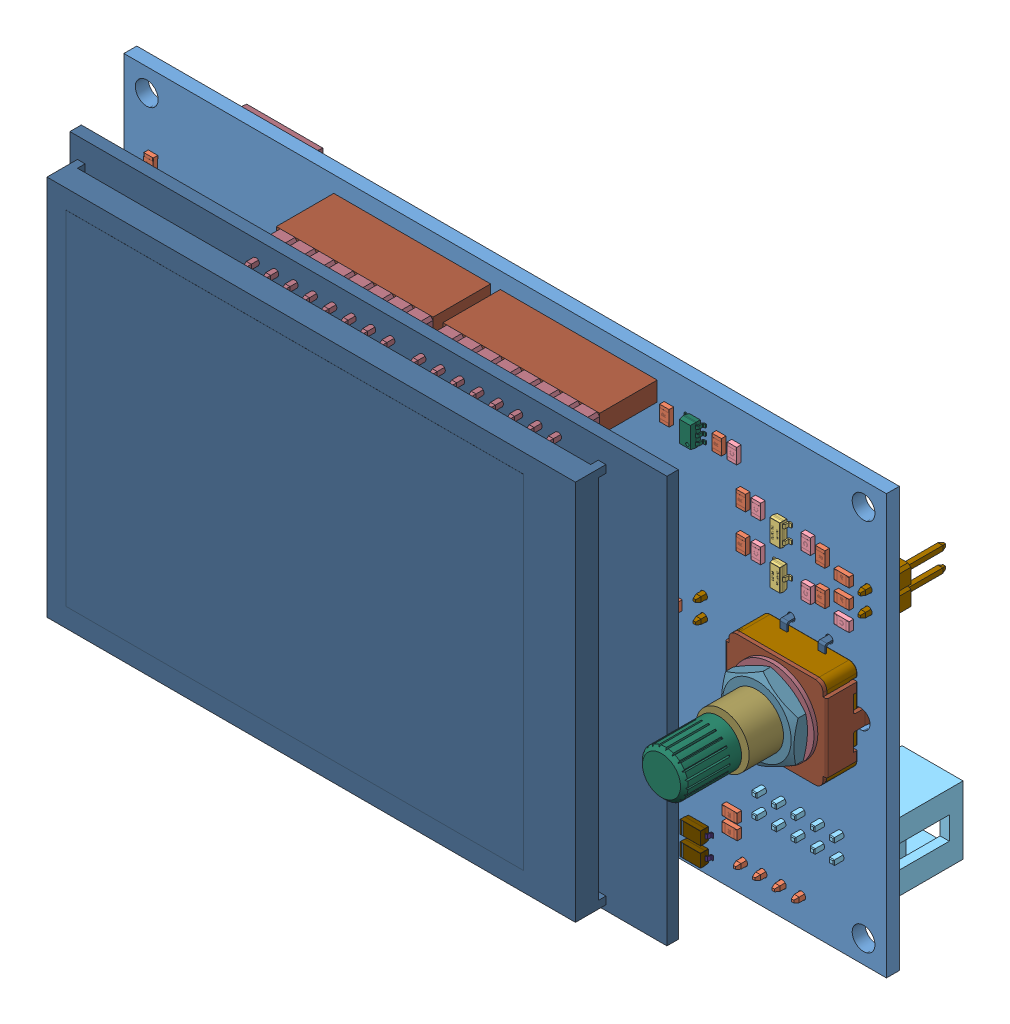
SolidWorks assembly JBC_SolderingIron, configuration Default. Lengths in mm.
Overall size (100 55 34.69).
305 component instances, 58 part files, 0 mates.
Components (placement in the parent):
- Board-1: Board [Default] at origin size (100 55 1.69)
  - Open CASCADE STEP translator 6.8 1.1.1-1: Open CASCADE STEP translator 6.8 1.1.1 [Default] at (0 0 -1.6914) size (100 55 1.69)
- R35-1: R35 [Default] at origin size (1.25 2 0.61)
  - 0805_Fekete_R-1: 0805_Fekete_R [Default] at (119.0962 50.0352 -0.35) x (0 -1 0) z (0 0 -1) size (2 1.25 0.61)
- R34-1: R34 [Default] at origin size (2 1.25 0.61)
  - 0805_Fekete_R-1: 0805_Fekete_R [Default] at (99.4752 5.4168 -0.35) x (-1 0 0) z (0 0 -1) size (2 1.25 0.61)
- R33-1: R33 [Default] at origin size (1.25 2 0.61)
  - 0805_Fekete_R-1: 0805_Fekete_R [Default] at (54.2688 39.2928 -0.35) x (0 1 0) z (0 0 -1) size (2 1.25 0.61)
- Q4-1: Q4 [Default] at origin size (2.5 3.01 1.1)
  - SOT23-1: SOT23 [Default] at (86.4599 44.3231 0) x (0 -1 0) z (-1 0 0) size (3.01 1.1 2.5)
- C31-1: C31 [Default] at origin size (1.25 2 0.61)
  - 0805_Barna_C-1: 0805_Barna_C [Default] at (121.0963 50.0351 -0.35) x (0 -1 0) z (0 0 -1) size (2 1.25 0.61)
- C14-1: C14 [Default] at origin size (1.25 2 0.61)
  - 0805_Barna_C-1: 0805_Barna_C [Default] at (52.3637 39.8009 -0.35) x (0 1 0) z (0 0 -1) size (2 1.25 0.61)
- C29-1: C29 [Default] at origin size (11.6 10.3 10.2)
  - User_Library-ALU-G-1: User_Library-ALU-G [Default] at (26.6701 17.1449 -1.6914) x (1 0 0) z (0 0 -1) size (11.6 10.3 10.2)
    - Pins_1-1: Pins_1 [Default] at origin size (11.6 0.9 0.35)
    - Fuss_1-1: Fuss_1 [Default] at origin size (10.3 10.3 1)
    - K_X_F6rper_1-1: K_X_F6rper_1 [Default] at origin size (10 10 9.5)
    - Beschriftung_1-1: Beschriftung_1 [Default] at origin size (7.49 8.07 0.06)
- C30-1: C30 [Default] at origin size (11.6 10.3 10.2)
  - User_Library-ALU-G-1: User_Library-ALU-G [Default] at (26.6701 28.5749 -1.6914) x (1 0 0) z (0 0 -1) size (11.6 10.3 10.2)
    - Pins_1-1: Pins_1 [Default] at origin size (11.6 0.9 0.35)
    - Fuss_1-1: Fuss_1 [Default] at origin size (10.3 10.3 1)
    - K_X_F6rper_1-1: K_X_F6rper_1 [Default] at origin size (10 10 9.5)
    - Beschriftung_1-1: Beschriftung_1 [Default] at origin size (7.49 8.07 0.06)
- J4-1: J4 [Default] at origin size (2.5 5.08 11.2)
  - SIL2-1: SIL2 [Default] at (97.6199 41.7829 -1.7914) x (0 -1 0) z (-1 0 0) size (5.08 11.2 2.5)
- R28-1: R28 [Default] at origin size (2 1.25 0.61)
  - 0805_Fekete_R-1: 0805_Fekete_R [Default] at (75.2338 46.5262 -0.35) x (1 0 0) z (0 0 -1) size (2 1.25 0.61)
- R27-1: R27 [Default] at origin size (2 1.25 0.61)
  - 0805_Fekete_R-1: 0805_Fekete_R [Default] at (75.2338 44.6212 -0.35) x (1 0 0) z (0 0 -1) size (2 1.25 0.61)
- C12-1: C12 [Default] at origin size (1.25 2 0.61)
  - 0805_Barna_C-1: 0805_Barna_C [Default] at (57.2213 33.6341 -0.35) x (0 -1 0) z (0 0 -1) size (2 1.25 0.61)
- C10-1: C10 [Default] at origin size (1.25 2 0.61)
  - 0805_Barna_C-1: 0805_Barna_C [Default] at (64.9413 35.8321 -0.35) x (0 -1 0) z (0 0 -1) size (2 1.25 0.61)
- C28-1: C28 [Default] at origin size (2 1.25 0.61)
  - 0805_Barna_C-1: 0805_Barna_C [Default] at (89.9229 75.6092 -0.35) x (1 0 0) z (0 0 -1) size (2 1.25 0.61)
- R32-1: R32 [Default] at origin size (2 1.25 0.61)
  - 0805_Fekete_R-1: 0805_Fekete_R [Default] at (29.1602 -7.5962 -0.35) x (-1 0 0) z (0 0 -1) size (2 1.25 0.61)
- R31-1: R31 [Default] at origin size (1.25 2 0.61)
  - 0805_Fekete_R-1: 0805_Fekete_R [Default] at (-8.4262 26.2798 -0.35) x (0 1 0) z (0 0 -1) size (2 1.25 0.61)
- R30-1: R30 [Default] at origin size (2 1.25 0.61)
  - 0805_Fekete_R-1: 0805_Fekete_R [Default] at (30.2942 84.8712 -1.3414) x (-1 0 0) z (0 0 1) size (2 1.25 0.61)
- R29-1: R29 [Default] at origin size (2 1.25 0.61)
  - 0805_Fekete_R-1: 0805_Fekete_R [Default] at (28.2502 82.4812 -1.3414) x (-1 0 0) z (0 0 1) size (2 1.25 0.61)
- R21-1: R21 [Default] at origin size (2 1.25 0.61)
  - 0805_Fekete_R-1: 0805_Fekete_R [Default] at (34.6122 84.8712 -1.3414) x (-1 0 0) z (0 0 1) size (2 1.25 0.61)
- C7-1: C7 [Default] at origin size (1.25 2 0.61)
  - 0805_Barna_C-1: 0805_Barna_C [Default] at (49.3637 29.2761 -1.3414) x (0 -1 0) z (0 0 1) size (2 1.25 0.61)
- C4-1: C4 [Default] at origin size (1.25 2 0.61)
  - 0805_Barna_C-1: 0805_Barna_C [Default] at (130.6363 19.7239 -1.3414) x (0 1 0) z (0 0 1) size (2 1.25 0.61)
- C3-1: C3 [Default] at origin size (1.25 2 0.61)
  - 0805_Barna_C-1: 0805_Barna_C [Default] at (49.3637 33.4671 -1.3414) x (0 -1 0) z (0 0 1) size (2 1.25 0.61)
- C21-1: C21 [Default] at origin size (2 1.25 0.61)
  - 0805_Barna_C-1: 0805_Barna_C [Default] at (49.9939 1.9797 -1.3414) x (1 0 0) z (0 0 1) size (2 1.25 0.61)
- U1-1: U1 [Default] at origin size (78.3 53.34 20.75)
  - LCDassembly-1: LCDassembly [Default] at (43.644 27.5 -0.96) x (-1 0 0) z (0 0 1) size (78.3 53.34 20.75)
    - baseboard-1: baseboard [Default] at (-5.088 0 11.04) x (-1 0 0) z (0 0 1) size (78.3 53.34 6.51)
    - HEADER8-1: HEADER8 [Default] at (-16.01 -24.1265 0) x (-1 0 0) z (0 1 0) size (20.57 11.7 2.5)
    - SIL6-1: SIL6 [Default] at (-18.55 24.13 11.04) x (-1 0 0) z (0 1 0) size (15.24 11.2 2.5)
    - SIL8-1: SIL8 [Default] at (-16.01 -24.13 11.04) x (-1 0 0) z (0 1 0) size (20.32 11.2 2.5)
    - SIL8-2: SIL8 [Default] at (5.834 -24.13 11.04) x (-1 0 0) z (0 1 0) size (20.32 11.2 2.5)
    - SIL6-2: SIL6 [Default] at (-0.77 24.13 11.04) x (-1 0 0) z (0 1 0) size (15.24 11.2 2.5)
    - HEADER8-2: HEADER8 [Default] at (5.834 -24.1265 0) x (-1 0 0) z (0 1 0) size (20.57 11.7 2.5)
    - HEADER6-1: HEADER6 [Default] at (-18.55 24.1335 0) x (-1 0 0) z (0 1 0) size (15.49 11.7 2.5)
    - HEADER6-2: HEADER6 [Default] at (-0.77 24.1335 0) x (-1 0 0) z (0 1 0) size (15.49 11.7 2.5)
- U7-1: U7 [Default] at origin size (2.8 2.9 1.45)
  - User_Library-SOT23-6-2-1: User_Library-SOT23-6-2 [Default] at (75.015 49.9631 0) x (0 1 0) z (0 0 1) size (2.9 2.8 1.45)
- U9-1: U9 [Default] at origin size (6 4.9 1.7)
  - SO-8-1: SO-8 [Default] at (29.9501 41.5149 -1.6914) x (1 0 0) z (0 0 -1) size (6 4.9 1.7)
- U8-1: U8 [Default] at origin size (7 3.6 2.7)
  - SO4-170-2.54-1: SO4-170-2.54 [Default] at (38.0779 39.6149 -1.8914) x (0 -1 0) z (1 0 0) size (3.6 2.7 7)
- U6-1: U6 [Default] at origin size (9.32 21.8 15.2)
  - mps_dcdc_ncs3s_sc_a-1: mps_dcdc_ncs3s_sc_a [Default] at (40.46 7.62 2.3086) x (0 1 0) z (-1 0 0) size (21.8 15.2 9.32)
- U5-1: U5 [Default] at origin size (7 6.5 1.65)
  - User_Library-SOT-223-1-1: User_Library-SOT-223-1 [Default] at (48.7949 22.4851 0.75) x (1 0 0) z (0 -1 0) size (7 1.65 6.5)
- U4-1: U4 [Default] at origin size (11.77 11.77 1.57)
  - User_Library-LQFP64-0_5-1: User_Library-LQFP64-0_5 [Default] at (62.0001 34.33 -2.4414) x (0 1 0) z (0 0 -1) size (11.77 11.77 1.57)
- U3-1: U3 [Default] at origin size (7 3.6 2.7)
  - SO4-170-2.54-1: SO4-170-2.54 [Default] at (14.6051 32.7951 -1.8914) x (0 1 0) z (-1 0 0) size (3.6 2.7 7)
- U2-1: U2 [Default] at origin size (4.9 6 1.7)
  - SO-8-1: SO-8 [Default] at (33.0251 35.0089 0) x (0 -1 0) z (0 0 1) size (6 4.9 1.7)
- R19-1: R19 [Default] at origin size (1.25 2 0.61)
  - 0805_Fekete_R-1: 0805_Fekete_R [Default] at (109.0962 54.6732 -0.35) x (0 -1 0) z (0 0 -1) size (2 1.25 0.61)
- R18-1: R18 [Default] at origin size (1.25 2 0.61)
  - 0805_Fekete_R-1: 0805_Fekete_R [Default] at (115.9512 54.8052 -0.35) x (0 -1 0) z (0 0 -1) size (2 1.25 0.61)
- R22-1: R22 [Default] at origin size (2 1.25 0.61)
  - 0805_Fekete_R-1: 0805_Fekete_R [Default] at (28.2502 76.7547 -1.3414) x (-1 0 0) z (0 0 1) size (2 1.25 0.61)
- R25-1: R25 [Default] at origin size (2 1.25 0.61)
  - 0805_Fekete_R-1: 0805_Fekete_R [Default] at (50.2238 70.9662 -0.35) x (1 0 0) z (0 0 -1) size (2 1.25 0.61)
- R26-1: R26 [Default] at origin size (2 1.25 0.61)
  - 0805_Fekete_R-1: 0805_Fekete_R [Default] at (38.6382 73.9812 -1.3414) x (-1 0 0) z (0 0 1) size (2 1.25 0.61)
- R20-1: R20 [Default] at origin size (2 1.25 0.61)
  - 0805_Fekete_R-1: 0805_Fekete_R [Default] at (30.2942 74.7112 -1.3414) x (-1 0 0) z (0 0 1) size (2 1.25 0.61)
- R23-1: R23 [Default] at origin size (1.25 2 0.61)
  - 0805_Fekete_R-1: 0805_Fekete_R [Default] at (100.3862 32.3401 -0.35) x (0 -1 0) z (0 0 -1) size (2 1.25 0.61)
- R24-1: R24 [Default] at origin size (2 1.25 0.61)
  - 0805_Fekete_R-1: 0805_Fekete_R [Default] at (76.9962 -8.6802 -0.35) x (-1 0 0) z (0 0 -1) size (2 1.25 0.61)
- R13-1: R13 [Default] at origin size (1.25 2 0.61)
  - 0805_Fekete_R-1: 0805_Fekete_R [Default] at (129.5412 44.2732 -0.35) x (0 -1 0) z (0 0 -1) size (2 1.25 0.61)
- R17-1: R17 [Default] at origin size (2 1.25 0.61)
  - 0805_Fekete_R-1: 0805_Fekete_R [Default] at (7.6448 -8.0162 -1.3414) x (1 0 0) z (0 0 1) size (2 1.25 0.61)
- R14-1: R14 [Default] at origin size (1.25 2 0.61)
  - 0805_Fekete_R-1: 0805_Fekete_R [Default] at (41.4462 49.4212 -0.35) x (0 -1 0) z (0 0 -1) size (2 1.25 0.61)
- R16-1: R16 [Default] at origin size (1.25 2 0.61)
  - 0805_Fekete_R-1: 0805_Fekete_R [Default] at (119.0962 45.0352 -0.35) x (0 -1 0) z (0 0 -1) size (2 1.25 0.61)
- R12-1: R12 [Default] at origin size (2 1.25 0.61)
  - 0805_Fekete_R-1: 0805_Fekete_R [Default] at (50.4462 68.4062 -1.3414) x (-1 0 0) z (0 0 1) size (2 1.25 0.61)
- R11-1: R11 [Default] at origin size (1.25 2 0.61)
  - 0805_Fekete_R-1: 0805_Fekete_R [Default] at (47.1362 30.3048 -1.3414) x (0 1 0) z (0 0 1) size (2 1.25 0.61)
- R15-1: R15 [Default] at origin size (2 1.25 0.61)
  - 0805_Fekete_R-1: 0805_Fekete_R [Default] at (99.4752 2.8768 -0.35) x (-1 0 0) z (0 0 -1) size (2 1.25 0.61)
- R10-1: R10 [Default] at origin size (1.25 2 0.61)
  - 0805_Fekete_R-1: 0805_Fekete_R [Default] at (126.6362 19.7238 -1.3414) x (0 1 0) z (0 0 1) size (2 1.25 0.61)
- R9-1: R9 [Default] at origin size (1.25 2 0.61)
  - 0805_Fekete_R-1: 0805_Fekete_R [Default] at (-8.4262 30.5978 -0.35) x (0 1 0) z (0 0 -1) size (2 1.25 0.61)
- R8-1: R8 [Default] at origin size (1.25 2 0.61)
  - 0805_Fekete_R-1: 0805_Fekete_R [Default] at (-0.8062 35.1698 -0.35) x (0 1 0) z (0 0 -1) size (2 1.25 0.61)
- R7-1: R7 [Default] at origin size (1.25 2 0.61)
  - 0805_Fekete_R-1: 0805_Fekete_R [Default] at (1.0988 30.7248 -0.35) x (0 1 0) z (0 0 -1) size (2 1.25 0.61)
- R6-1: R6 [Default] at origin size (1.25 2 0.61)
  - 0805_Fekete_R-1: 0805_Fekete_R [Default] at (11.5898 30.6928 -0.35) x (0 1 0) z (0 0 -1) size (2 1.25 0.61)
- R5-1: R5 [Default] at origin size (2 1.25 0.61)
  - 0805_Fekete_R-1: 0805_Fekete_R [Default] at (46.4322 -3.1512 -0.35) x (-1 0 0) z (0 0 -1) size (2 1.25 0.61)
- R4-1: R4 [Default] at origin size (1.25 2 0.61)
  - 0805_Fekete_R-1: 0805_Fekete_R [Default] at (53.3638 29.2762 -1.3414) x (0 -1 0) z (0 0 1) size (2 1.25 0.61)
- R3-1: R3 [Default] at origin size (2 1.25 0.61)
  - 0805_Fekete_R-1: 0805_Fekete_R [Default] at (93.7602 69.5022 -1.3414) x (-1 0 0) z (0 0 1) size (2 1.25 0.61)
- R2-1: R2 [Default] at origin size (1.25 2 0.61)
  - 0805_Fekete_R-1: 0805_Fekete_R [Default] at (-16.0512 26.1138 -0.35) x (0 1 0) z (0 0 -1) size (2 1.25 0.61)
- R1-1: R1 [Default] at origin size (1.25 2 0.61)
  - 0805_Fekete_R-1: 0805_Fekete_R [Default] at (-0.8062 30.7248 -0.35) x (0 1 0) z (0 0 -1) size (2 1.25 0.61)
- Q3-1: Q3 [Default] at origin size (10 15.67 4.89)
  - SW3dPS-TO263-3S-1: SW3dPS-TO263-3S [Default] at (14.605 42.1801 -3.3414) x (-1 0 0) z (0 0 -1) size (10 15.67 4.89)
    - SW3dPS-TO263-3S_Board9-1: SW3dPS-TO263-3S_Board9 [Default] at (0 0 -0.0938) size (0.01 0.01 0.11)
    - SW3dPS-TO263-3S_Free-Models5-1: SW3dPS-TO263-3S_Free-Models5 [Default] at origin size (10 15.67 4.89)
      - SW3dPS-TO263-3S_450155985-1: SW3dPS-TO263-3S_450155985 [Default] at (2.54 -0.83 1.2127) size (1.2 1.68 0.6)
        - SW3dPS-TO263-3S_Extruded14-1: SW3dPS-TO263-3S_Extruded14 [Default] at origin size (1.2 1.68 0.6)
      - SW3dPS-TO263-3S_450154961-1: SW3dPS-TO263-3S_450154961 [Default] at (0.7 4.37 3.1727) size (0.72 1.1 0.19)
        - SW3dPS-TO263-3S_Extruded11-1: SW3dPS-TO263-3S_Extruded11 [Default] at origin size (0.72 1.1 0.19)
      - SW3dPS-TO263-3S_449923505-1: SW3dPS-TO263-3S_449923505 [Default] at (-3.9039 1.099 3.1727) size (1 1 0.01)
        - SW3dPS-TO263-3S_Cylinder1-1: SW3dPS-TO263-3S_Cylinder1 [Default] at origin size (1 1 0.01)
      - SW3dPS-TO263-3S_450155217-1: SW3dPS-TO263-3S_450155217 [Default] at (-1.115 4.37 3.1727) size (0.93 1.1 0.11)
        - SW3dPS-TO263-3S_Extruded12-1: SW3dPS-TO263-3S_Extruded12 [Default] at origin size (0.93 1.1 0.11)
      - SW3dPS-TO263-3S_450154833-1: SW3dPS-TO263-3S_450154833 [Default] at (1.555 4.37 3.1727) size (0.79 1.1 0.01)
        - SW3dPS-TO263-3S_Extruded21-1: SW3dPS-TO263-3S_Extruded21 [Default] at origin size (0.79 1.1 0.01)
      - SW3dPS-TO263-3S_450156369-1: SW3dPS-TO263-3S_450156369 [Default] at (0 -0.395 1.3127) size (1.2 0.81 0.5)
        - SW3dPS-TO263-3S_Extruded16-1: SW3dPS-TO263-3S_Extruded16 [Default] at origin size (1.2 0.81 0.5)
      - SW3dPS-TO263-3S_450155089-1: SW3dPS-TO263-3S_450155089 [Default] at (-0.165 4.37 3.1727) size (0.77 1.1 0.01)
        - SW3dPS-TO263-3S_Extruded19-1: SW3dPS-TO263-3S_Extruded19 [Default] at origin size (0.77 1.1 0.01)
      - SW3dPS-TO263-3S_450155985-2: SW3dPS-TO263-3S_450155985 [Default] at (-2.54 -0.83 1.2127) size (1.2 1.68 0.6)
        - SW3dPS-TO263-3S_Extruded14-1: SW3dPS-TO263-3S_Extruded14 [Default] at origin size (1.2 1.68 0.6)
      - SW3dPS-TO263-3S_PIN1-1: SW3dPS-TO263-3S_PIN1 [Default] at (-2.5273 -0.09 1.5627) x (0 1 0) z (-1 0 0) size (5 3.43 0.8)
        - SW3dPS-TO263-3S_Board5-1: SW3dPS-TO263-3S_Board5 [Default] at (0 0 -0.0938) size (0.01 0.01 0.11)
        - SW3dPS-TO263-3S_Free-Models6-1: SW3dPS-TO263-3S_Free-Models6 [Default] at origin size (5 3.43 0.8)
          - SW3dPS-TO263-3S_453496145-1: SW3dPS-TO263-3S_453496145 [Default] at (-2.4 1.465 -0.3873) size (5 3.43 0.8)
            - SW3dPS-TO263-3S_Extruded13-1: SW3dPS-TO263-3S_Extruded13 [Default] at origin size (5 3.43 0.8)
      - SW3dPS-TO263-3S_BODY3-1: SW3dPS-TO263-3S_BODY3 [Default] at (0 0.1 0.0127) size (10 10.68 4.78)
        - SW3dPS-TO263-3S_Free-Models7-1: SW3dPS-TO263-3S_Free-Models7 [Default] at origin size (10 10.68 4.78)
          - SW3dPS-TO263-3S_BODY4-1: SW3dPS-TO263-3S_BODY4 [Default] at (0.0127 0 1.5827) x (0 0 1) z (-1 0 0) size (3.15 9 10)
            - SW3dPS-TO263-3S_Free-Models8-1: SW3dPS-TO263-3S_Free-Models8 [Default] at origin size (3.15 9 10)
              - SW3dPS-TO263-3S_453496017-1: SW3dPS-TO263-3S_453496017 [Default] at (0 4.4 -4.9873) size (3.15 9 10)
                - SW3dPS-TO263-3S_Extruded18-1: SW3dPS-TO263-3S_Extruded18 [Default] at origin size (3.15 9 10)
            - SW3dPS-TO263-3S_Board7-1: SW3dPS-TO263-3S_Board7 [Default] at (0 0 -0.0938) size (0.01 0.01 0.11)
          - SW3dPS-TO263-3S_BODY5-1: SW3dPS-TO263-3S_BODY5 [Default] at (0 0 0.0127) size (10 10.68 1.65)
            - SW3dPS-TO263-3S_Board6-1: SW3dPS-TO263-3S_Board6 [Default] at (0 0 -0.0938) size (0.01 0.01 0.11)
            - SW3dPS-TO263-3S_Free-Models9-1: SW3dPS-TO263-3S_Free-Models9 [Default] at origin size (10 10.68 1.65)
              - SW3dPS-TO263-3S_453494353-1: SW3dPS-TO263-3S_453494353 [Default] at (0 7.15 -1.6373) size (10 6.86 1.65)
                - SW3dPS-TO263-3S_Extruded15-1: SW3dPS-TO263-3S_Extruded15 [Default] at origin size (10 6.86 1.65)
              - SW3dPS-TO263-3S_453494225-1: SW3dPS-TO263-3S_453494225 [Default] at (0 4.4 -1.6373) size (10 9 1.65)
                - SW3dPS-TO263-3S_Extruded17-1: SW3dPS-TO263-3S_Extruded17 [Default] at origin size (10 9 1.65)
        - SW3dPS-TO263-3S_Board8-1: SW3dPS-TO263-3S_Board8 [Default] at (0 0 -0.0938) size (0.01 0.01 0.11)
      - SW3dPS-TO263-3S_PIN1-2: SW3dPS-TO263-3S_PIN1 [Default] at (2.5527 -0.09 1.5627) x (0 1 0) z (-1 0 0) size (5 3.43 0.8)
        - SW3dPS-TO263-3S_Board5-1: SW3dPS-TO263-3S_Board5 [Default] at (0 0 -0.0938) size (0.01 0.01 0.11)
        - SW3dPS-TO263-3S_Free-Models6-1: SW3dPS-TO263-3S_Free-Models6 [Default] at origin size (5 3.43 0.8)
          - SW3dPS-TO263-3S_453496145-1: SW3dPS-TO263-3S_453496145 [Default] at (-2.4 1.465 -0.3873) size (5 3.43 0.8)
            - SW3dPS-TO263-3S_Extruded13-1: SW3dPS-TO263-3S_Extruded13 [Default] at origin size (5 3.43 0.8)
      - SW3dPS-TO263-3S_450155473-1: SW3dPS-TO263-3S_450155473 [Default] at (-1.945 4.37 3.1727) size (0.77 1.1 0.01)
        - SW3dPS-TO263-3S_Extruded20-1: SW3dPS-TO263-3S_Extruded20 [Default] at origin size (0.77 1.1 0.01)
- Q2-1: Q2 [Default] at origin size (2.5 3.01 1.1)
  - SOT23-1: SOT23 [Default] at (86.4601 39.2429 0) x (0 1 0) z (1 0 0) size (3.01 1.1 2.5)
- Q1-1: Q1 [Default] at origin size (3.01 2.5 1.1)
  - SOT23-1: SOT23 [Default] at (45.9899 35.4849 0) x (1 0 0) z (0 -1 0) size (3.01 1.1 2.5)
- JP1-1: JP1 [Default] at origin size (2.5 5.08 11.2)
  - SIL2-1: SIL2 [Default] at (76.0301 30.2261 -1.7914) x (0 1 0) z (1 0 0) size (5.08 11.2 2.5)
- JP2-1: JP2 [Default] at origin size (2.5 5.08 11.2)
  - SIL2-1: SIL2 [Default] at (76.2001 12.0651 -1.7914) x (0 1 0) z (1 0 0) size (5.08 11.2 2.5)
- J6-1: J6 [Default] at origin size (10.16 2.5 11.2)
  - SIL4-1: SIL4 [Default] at (85.0901 3.8099 -1.7914) x (1 0 0) z (0 -1 0) size (10.16 11.2 2.5)
- J5-1: J5 [Default] at origin size (8 10 13.5)
  - TB2-1: TB2 [Default] at (8.4073 22.3399 -11.7914) x (0 1 0) z (-1 0 0) size (10 13.5 8)
    - User_Library-TB2_TB_case_1-1: User_Library-TB2_TB_case_1 [Default] at (-10 0 0) x (0 0 1) z (0 1 0) size (8 10 10)
    - User_Library-TB2_TB_screw_1-1: User_Library-TB2_TB_screw_1 [Default] at (-2.5 -4.6 4.6) x (-1 0 0) z (0 0 -1) size (3.9 11.9 3.9)
    - User_Library-TB2_TB_screw_1-2: User_Library-TB2_TB_screw_1 [Default] at (-7.5 -4.6 4.6) size (3.9 11.9 3.9)
- J3-1: J3 [Default] at origin size (8 10 13.5)
  - TB2-1: TB2 [Default] at (8.4073 32.4999 -11.7914) x (0 1 0) z (-1 0 0) size (10 13.5 8)
    - User_Library-TB2_TB_case_1-1: User_Library-TB2_TB_case_1 [Default] at (-10 0 0) x (0 0 1) z (0 1 0) size (8 10 10)
    - User_Library-TB2_TB_screw_1-1: User_Library-TB2_TB_screw_1 [Default] at (-2.5 -4.6 4.6) x (-1 0 0) z (0 0 -1) size (3.9 11.9 3.9)
    - User_Library-TB2_TB_screw_1-2: User_Library-TB2_TB_screw_1 [Default] at (-7.5 -4.6 4.6) size (3.9 11.9 3.9)
- J2-1: J2 [Default] at origin size (8 10 13.5)
  - TB2-1: TB2 [Default] at (8.4073 42.6599 -11.7914) x (0 1 0) z (-1 0 0) size (10 13.5 8)
    - User_Library-TB2_TB_case_1-1: User_Library-TB2_TB_case_1 [Default] at (-10 0 0) x (0 0 1) z (0 1 0) size (8 10 10)
    - User_Library-TB2_TB_screw_1-1: User_Library-TB2_TB_screw_1 [Default] at (-2.5 -4.6 4.6) x (-1 0 0) z (0 0 -1) size (3.9 11.9 3.9)
    - User_Library-TB2_TB_screw_1-2: User_Library-TB2_TB_screw_1 [Default] at (-7.5 -4.6 4.6) size (3.9 11.9 3.9)
- J1-1: J1 [Default] at origin size (20.5 9.3 12.1)
  - BH-10_64-1: BH-10_64 [Default] at (83.8201 13.335 -1.7914) x (1 0 0) z (0 1 0) size (20.5 12.1 9.3)
- F2-1: F2 [Default] at origin size (3.41 4.73 1.34)
  - 1812L-1: 1812L [Default] at (34.1851 13.0584 0) x (0 -1 0) z (0 0 1) size (4.73 3.41 1.34)
- F1-1: F1 [Default] at origin size (9.4 24.4 17)
  - 696107003002-1: 696107003002 [Default] at (19.3049 14.4939 -3.1914) x (0 -1 0) z (0 0 -1) size (24.4 9.4 15)
  - 696107003002_2-1: 696107003002_2 [Default] at (19.3049 14.4939 -3.1914) x (0 -1 0) z (0 0 -1) size (24.4 9.4 8.4)
- EN1-1: EN1 [Default] at origin size (14.62 14.7 23.24)
  - PEC11_4220_S0024-1: PEC11_4220_S0024 [Default] at (90.0001 27.7501 0) x (1 0 0) z (0 0 1) size (14.62 14.7 23.24)
    - 12mm_Incremental_Encoder_Base_1-1: 12mm_Incremental_Encoder_Base_1 [Default] at origin size (12.36 12 4)
    - 12mm_Incremental_Encoder_Pin_1-1: 12mm_Incremental_Encoder_Pin_1 [Default] at (0 -6.6 0.8) x (0 -1 0) z (-1 0 0) size (3 4.4 0.9)
    - 12mm_Incremental_Encoder_Pin_1-2: 12mm_Incremental_Encoder_Pin_1 [Default] at (2.5 6.1 0.8) x (0 1 0) z (1 0 0) size (3 4.4 0.9)
    - 12mm_Incremental_Encoder_Pin_1-3: 12mm_Incremental_Encoder_Pin_1 [Default] at (-2.5 6.1 0.8) x (0 1 0) z (1 0 0) size (3 4.4 0.9)
    - 12mm_Incremental_Encoder_Pin_1-4: 12mm_Incremental_Encoder_Pin_1 [Default] at (-2.5 -6.6 0.8) x (0 -1 0) z (-1 0 0) size (3 4.4 0.9)
    - 12mm_Incremental_Encoder_Pin_1-5: 12mm_Incremental_Encoder_Pin_1 [Default] at (2.5 -6.6 0.8) x (0 -1 0) z (-1 0 0) size (3 4.4 0.9)
    - 12mm_Incremental_Encoder_Anti-Rotation_Plate_1-1: 12mm_Incremental_Encoder_Anti-Rotation_Plate_1 [Default] at (0 0 4) size (14.62 12 8.24)
    - 12mm_Incremental_Encoder_Threaded_Tube_1-1: 12mm_Incremental_Encoder_Threaded_Tube_1 [Default] at (-5.8861 -2.5756 11.5) x (-0.916131 -0.400879 0) z (0 0 -1) size (7 7 7)
    - 12mm_Incremental_Encoder_Washer_1-1: 12mm_Incremental_Encoder_Washer_1 [Default] at (6.424 -0.1143 4.5) x (0.999842 -0.017794 0) z (0 0 1) size (11 11 0.5)
    - M7x0.75_Hex_Nut_1-1: M7x0.75_Hex_Nut_1 [Default] at (0 0 5) x (0.835271 -0.549838 0) z (0 0 1) size (11 9.53 2)
    - 12mm_Incremental_Encoder_Shaft-1: 12mm_Incremental_Encoder_Shaft [Default] at (0 0 11.5) x (0.652489 0.757799 0) z (0 0 1) size (6 6 13)
- D6-1: D6 [Default] at origin size (3.75 1.71 1.2)
  - sod123_v4-1: sod123_v4 [Default] at (75.4701 4.8401 0) x (1 0 0) z (0 0 1) size (3.75 1.71 1.2)
    - pin-1: pin [Default] at (-0.675 -0.875 0) x (0 -1 0) z (0 0 1) size (0.55 0.55 0.6)
    - pin(Mirror)-1: pin(Mirror) [Default] at (0.675 -0.875 0) x (0 -1 0) z (0 0 -1) size (0.55 0.55 0.6)
    - icbody-1: icbody [Default] at origin size (2.71 1.71 1.11)
    - Component5-1: Component5 [Default] at origin size (0.2 1.7 0.02)
- D3-1: D3 [Default] at origin size (3.75 1.71 1.2)
  - sod123_v4-1: sod123_v4 [Default] at (75.4701 2.3001 0) x (1 0 0) z (0 0 1) size (3.75 1.71 1.2)
    - pin-1: pin [Default] at (-0.675 -0.875 0) x (0 -1 0) z (0 0 1) size (0.55 0.55 0.6)
    - pin(Mirror)-1: pin(Mirror) [Default] at (0.675 -0.875 0) x (0 -1 0) z (0 0 -1) size (0.55 0.55 0.6)
    - icbody-1: icbody [Default] at origin size (2.71 1.71 1.11)
    - Component5-1: Component5 [Default] at origin size (0.2 1.7 0.02)
- D5-1: D5 [Default] at origin size (3.75 1.71 1.2)
  - sod123_v4-1: sod123_v4 [Default] at (27.9841 20.0661 0) x (1 0 0) z (0 0 1) size (3.75 1.71 1.2)
    - pin-1: pin [Default] at (-0.675 -0.875 0) x (0 -1 0) z (0 0 1) size (0.55 0.55 0.6)
    - pin(Mirror)-1: pin(Mirror) [Default] at (0.675 -0.875 0) x (0 -1 0) z (0 0 -1) size (0.55 0.55 0.6)
    - icbody-1: icbody [Default] at origin size (2.71 1.71 1.11)
    - Component5-1: Component5 [Default] at origin size (0.2 1.7 0.02)
- D4-1: D4 [Default] at origin size (3.75 1.71 1.2)
  - sod123_v4-1: sod123_v4 [Default] at (27.3899 11.0899 0) x (-1 0 0) z (0 0 1) size (3.75 1.71 1.2)
    - pin-1: pin [Default] at (-0.675 -0.875 0) x (0 -1 0) z (0 0 1) size (0.55 0.55 0.6)
    - pin(Mirror)-1: pin(Mirror) [Default] at (0.675 -0.875 0) x (0 -1 0) z (0 0 -1) size (0.55 0.55 0.6)
    - icbody-1: icbody [Default] at origin size (2.71 1.71 1.11)
    - Component5-1: Component5 [Default] at origin size (0.2 1.7 0.02)
- D2-1: D2 [Default] at origin size (3.01 2.5 1.1)
  - SOT23-1: SOT23 [Default] at (24.1299 35.3739 0) x (1 0 0) z (0 -1 0) size (3.01 1.1 2.5)
- D1-1: D1 [Default] at origin size (3.01 2.5 1.1)
  - SOT23-1: SOT23 [Default] at (20.6351 35.3741 0) x (-1 0 0) z (0 1 0) size (3.01 1.1 2.5)
- C23-1: C23 [Default] at origin size (2 1.25 0.61)
  - 0805_Barna_C-1: 0805_Barna_C [Default] at (18.6979 5.3037 -1.3414) x (1 0 0) z (0 0 1) size (2 1.25 0.61)
- C27-1: C27 [Default] at origin size (1.25 2 0.61)
  - 0805_Barna_C-1: 0805_Barna_C [Default] at (103.3863 32.3401 -0.35) x (0 -1 0) z (0 0 -1) size (2 1.25 0.61)
- C26-1: C26 [Default] at origin size (2 1.25 0.61)
  - 0805_Barna_C-1: 0805_Barna_C [Default] at (59.7761 -2.3063 -0.35) x (-1 0 0) z (0 0 -1) size (2 1.25 0.61)
- C25-1: C25 [Default] at origin size (1.25 2 0.61)
  - 0805_Barna_C-1: 0805_Barna_C [Default] at (71.2913 33.8001 -0.35) x (0 -1 0) z (0 0 -1) size (2 1.25 0.61)
- C24-1: C24 [Default] at origin size (2 1.25 0.61)
  - 0805_Barna_C-1: 0805_Barna_C [Default] at (28.2501 78.6713 -1.3414) x (-1 0 0) z (0 0 1) size (2 1.25 0.61)
- C22-1: C22 [Default] at origin size (1.25 2 0.61)
  - 0805_Barna_C-1: 0805_Barna_C [Default] at (5.7417 44.6211 -1.3414) x (0 -1 0) z (0 0 1) size (2 1.25 0.61)
- C19-1: C19 [Default] at origin size (2 1.25 0.61)
  - 0805_Barna_C-1: 0805_Barna_C [Default] at (25.0599 7.6937 -1.3414) x (1 0 0) z (0 0 1) size (2 1.25 0.61)
- C20-1: C20 [Default] at origin size (1.25 2 0.61)
  - 0805_Barna_C-1: 0805_Barna_C [Default] at (99.2312 46.0351 -0.35) x (0 -1 0) z (0 0 -1) size (2 1.25 0.61)
- C11-1: C11 [Default] at origin size (11.6 10.3 10.2)
  - User_Library-ALU-G-1: User_Library-ALU-G [Default] at (26.6701 5.7149 -1.6914) x (1 0 0) z (0 0 -1) size (11.6 10.3 10.2)
    - Pins_1-1: Pins_1 [Default] at origin size (11.6 0.9 0.35)
    - Fuss_1-1: Fuss_1 [Default] at origin size (10.3 10.3 1)
    - K_X_F6rper_1-1: K_X_F6rper_1 [Default] at origin size (10 10 9.5)
    - Beschriftung_1-1: Beschriftung_1 [Default] at origin size (7.49 8.07 0.06)
- C13-1: C13 [Default] at origin size (1.25 2 0.61)
  - 0805_Barna_C-1: 0805_Barna_C [Default] at (75.3143 13.4121 -0.35) x (0 -1 0) z (0 0 -1) size (2 1.25 0.61)
- C18-1: C18 [Default] at origin size (2 1.25 0.61)
  - 0805_Barna_C-1: 0805_Barna_C [Default] at (53.6871 -21.5663 -0.35) x (-1 0 0) z (0 0 -1) size (2 1.25 0.61)
- C17-1: C17 [Default] at origin size (3.39 1.6 1.65)
  - User_Library-Tantalum_Capacitor_Case_A-1: User_Library-Tantalum_Capacitor_Case_A [Default] at (49.4191 13.5301 0.05) x (1 0 0) z (0 0 1) size (3.39 1.6 1.65)
    - User_Library-Tantalum_Capacitor_Case_A_Tantalum_case_A_part1-1: User_Library-Tantalum_Capacitor_Case_A_Tantalum_case_A_part1 [Default] at (-1.5973 -0.8 0.1) size (3.2 1.6 1.6)
    - User_Library-Tantalum_Capacitor_Case_A_Tantalum_case_A_part2-1: User_Library-Tantalum_Capacitor_Case_A_Tantalum_case_A_part2 [Default] at (-0.8925 -0.6 0.05) x (-1 0 0) z (0 0 -1) size (0.8 1.2 0.9)
    - User_Library-Tantalum_Capacitor_Case_A_Tantalum_case_A_part2-2: User_Library-Tantalum_Capacitor_Case_A_Tantalum_case_A_part2 [Default] at (0.8979 0.6 0.05) x (1 0 0) z (0 0 -1) size (0.8 1.2 0.9)
- C16-1: C16 [Default] at origin size (3.39 1.6 1.65)
  - User_Library-Tantalum_Capacitor_Case_A-1: User_Library-Tantalum_Capacitor_Case_A [Default] at (50.2709 27.4999 0.05) x (-1 0 0) z (0 0 1) size (3.39 1.6 1.65)
    - User_Library-Tantalum_Capacitor_Case_A_Tantalum_case_A_part1-1: User_Library-Tantalum_Capacitor_Case_A_Tantalum_case_A_part1 [Default] at (-1.5973 -0.8 0.1) size (3.2 1.6 1.6)
    - User_Library-Tantalum_Capacitor_Case_A_Tantalum_case_A_part2-1: User_Library-Tantalum_Capacitor_Case_A_Tantalum_case_A_part2 [Default] at (-0.8925 -0.6 0.05) x (-1 0 0) z (0 0 -1) size (0.8 1.2 0.9)
    - User_Library-Tantalum_Capacitor_Case_A_Tantalum_case_A_part2-2: User_Library-Tantalum_Capacitor_Case_A_Tantalum_case_A_part2 [Default] at (0.8979 0.6 0.05) x (1 0 0) z (0 0 -1) size (0.8 1.2 0.9)
- C15-1: C15 [Default] at origin size (1.25 2 0.61)
  - 0805_Barna_C-1: 0805_Barna_C [Default] at (-6.5213 24.2479 -0.35) x (0 1 0) z (0 0 -1) size (2 1.25 0.61)
- C9-1: C9 [Default] at origin size (1.25 2 0.61)
  - 0805_Barna_C-1: 0805_Barna_C [Default] at (121.0963 45.0351 -0.35) x (0 -1 0) z (0 0 -1) size (2 1.25 0.61)
- C8-1: C8 [Default] at origin size (1.25 2 0.61)
  - 0805_Barna_C-1: 0805_Barna_C [Default] at (127.6363 43.7651 -0.35) x (0 -1 0) z (0 0 -1) size (2 1.25 0.61)
- C6-1: C6 [Default] at origin size (1.25 2 0.61)
  - 0805_Barna_C-1: 0805_Barna_C [Default] at (78.2763 42.1821 -0.35) x (0 -1 0) z (0 0 -1) size (2 1.25 0.61)
- C5-1: C5 [Default] at origin size (1.25 2 0.61)
  - 0805_Barna_C-1: 0805_Barna_C [Default] at (80.3083 42.1821 -0.35) x (0 -1 0) z (0 0 -1) size (2 1.25 0.61)
- C2-1: C2 [Default] at origin size (1.25 2 0.61)
  - 0805_Barna_C-1: 0805_Barna_C [Default] at (64.9413 40.1501 -0.35) x (0 -1 0) z (0 0 -1) size (2 1.25 0.61)
- C1-1: C1 [Default] at origin size (1.25 2 0.61)
  - 0805_Barna_C-1: 0805_Barna_C [Default] at (117.9513 54.8051 -0.35) x (0 -1 0) z (0 0 -1) size (2 1.25 0.61)
- B1-1: B1 [Default] at origin size (6.2 4.7 1.75)
  - SOIC-4_(Fairchild)-1: SOIC-4_(Fairchild) [Default] at (22.6799 15.5151 0) x (0 -1 0) z (-1 0 0) size (4.7 1.75 6.2)
